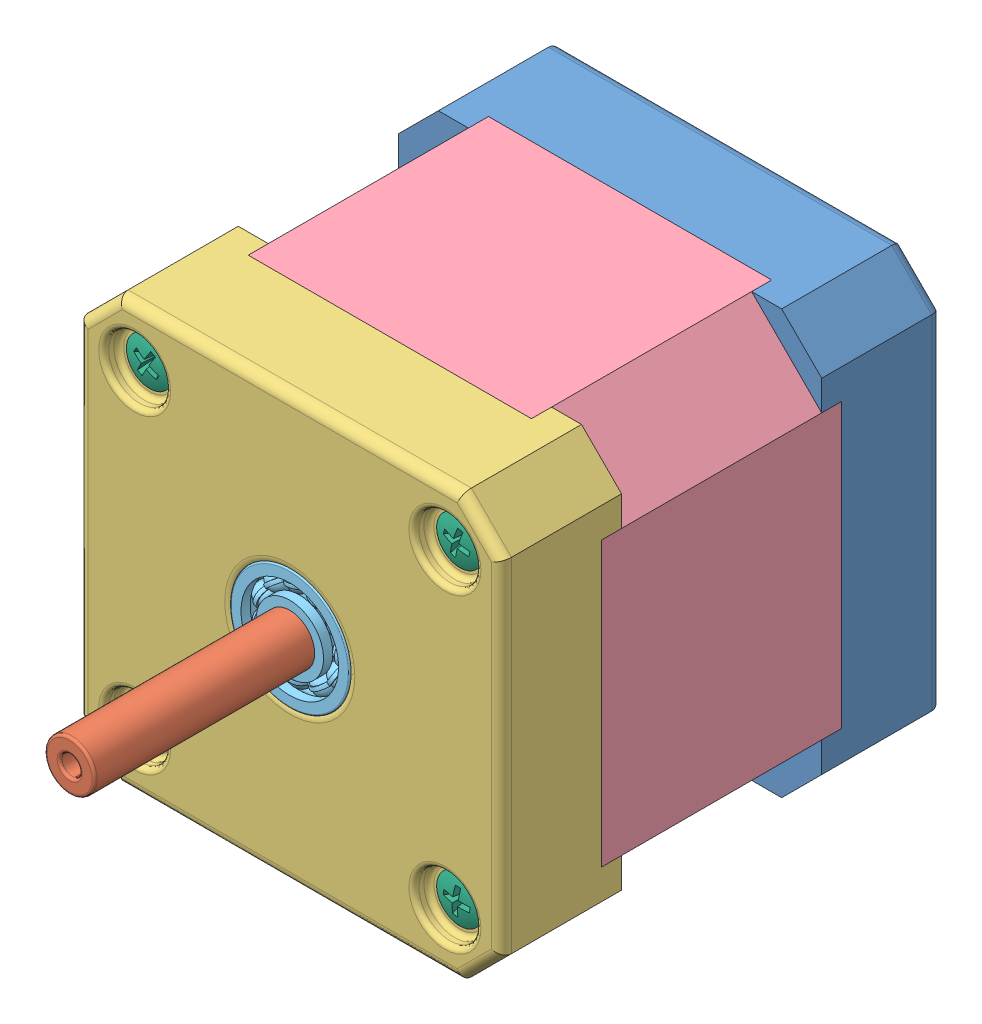
SolidWorks assembly stepper, configuration Default. Lengths in mm.
Overall size (84.6 84.6 136).
10 component instances, 6 part files, 20 mates.
Components (placement in the parent):
- backPlate-1: backPlate [Default] at (30.6882 45.002 54.8281) size (84.6 84.6 28)
- arbre axiale-1: arbre axiale [Default] at (30.6882 45.002 50.8281) x (-0.859783 -0.510659 0) z (0 0 1) size (10 10 136)
- base-1: base [Default] at (72.9882 2.702 142.8281) x (-1 0 0) z (0 0 -1) size (84.6 84.6 24)
- body-1: body [Default] at (30.6882 45.002 74.8281) size (84.6 84.6 48)
- instrument ball bearing_68_am-4: instrument ball bearing_68_am [AFBMA 12.1.4.1 - 0090-24 - Full,DE,AC,Full_68] at (30.6882 45.002 139.3281) x (0 0 1) z (-0.918452 0.395532 0) size (7 24 24)
- instrument ball bearing_68_am-5: instrument ball bearing_68_am [AFBMA 12.1.4.1 - 0090-24 - Full,DE,AC,Full_68] at (30.6882 45.002 61.3281) x (0 0 1) z (-0.976788 0.214208 0) size (7 24 24)
- oval head_am-1: oval head_am [B18.6.7M - M5 x 0.8 x 13 Type I Cross Recessed OHMS --13S] at (61.6882 76.002 140.7742) x (0 0 -1) z (0.276926 0.960891 0) size (14.17 9.3 9.3)
- oval head_am-2: oval head_am [B18.6.7M - M5 x 0.8 x 13 Type I Cross Recessed OHMS --13S] at (61.6882 14.002 140.7742) x (0 0 -1) z (0.994132 -0.108176 0) size (14.17 9.3 9.3)
- oval head_am-3: oval head_am [B18.6.7M - M5 x 0.8 x 13 Type I Cross Recessed OHMS --13S] at (-0.3118 76.002 140.7742) x (0 0 -1) z (0.86317 -0.504913 0) size (14.17 9.3 9.3)
- oval head_am-4: oval head_am [B18.6.7M - M5 x 0.8 x 13 Type I Cross Recessed OHMS --13S] at (-0.3118 14.002 140.7742) x (0 0 -1) z (1 0 0) size (14.17 9.3 9.3)
Mates (geometry in assembly coordinates):
- Concentric1: concentric: cylinder of assembly; cylinder of assembly; cylinder of backPlate-1 through (30.6882 45.002 78.8281) axis (0 0 -1) radius 5; cylinder of arbre axiale-1 through (30.6882 45.002 186.8281) axis (0 0 -1) radius 5
- Coincident1: coincident: plane of assembly; plane of assembly; plane of backPlate-1 through (58.9882 87.302 74.8281) normal (-0.707107 -0.707107 0); plane of body-1 through (58.9882 87.302 122.8281) normal (0.707107 0.707107 0)
- Coincident2: coincident: plane of assembly; plane of assembly; plane of backPlate-1 through (-11.6118 73.302 74.8281) normal (0.707107 -0.707107 0); plane of body-1 through (-11.6118 73.302 122.8281) normal (-0.707107 0.707107 0)
- Coincident3: coincident: plane of assembly; plane of assembly; plane of backPlate-1 through (30.6882 45.002 50.8281) normal (0 0 -1); plane of arbre axiale-1 through (30.6882 45.002 50.8281) normal (0 0 -1)
- Concentric2: concentric: cylinder of assembly; cylinder of assembly; cylinder of arbre axiale-1 through (30.6882 45.002 186.8281) axis (0 0 -1) radius 5; cylinder of base-1 through (30.6882 45.002 118.8281) axis (0 0 1) radius 5
- Coincident4: coincident: plane of assembly; plane of assembly; plane of base-1 through (72.9882 73.302 122.8281) normal (-0.707107 -0.707107 0); plane of body-1 through (58.9882 87.302 122.8281) normal (0.707107 0.707107 0)
- Coincident5: coincident: plane of assembly; plane of assembly; plane of backPlate-1 through (30.6882 45.002 74.8281) normal (0 0 1); plane of body-1 through (30.6882 45.002 74.8281) normal (0 0 -1)
- Coincident6: coincident: plane of assembly; plane of assembly; plane of base-1 through (72.9882 2.702 122.8281) normal (0 0 -1); plane of body-1 through (30.6882 45.002 122.8281) normal (0 0 1)
- Concentric5: concentric: cylinder of assembly; cylinder of assembly; cylinder of arbre axiale-1 through (30.6882 45.002 186.8281) axis (0 0 -1) radius 5; cylinder of instrument ball bearing_68_am-4 through (30.6882 45.002 118.6906) axis (0 0 1) radius 4.5
- Coincident7: coincident: plane of assembly; plane of assembly; plane of base-1 through (72.9882 2.702 142.8281) normal (0 0 1); plane of instrument ball bearing_68_am-4 through (35.316 55.7479 142.8281) normal (0 0 1)
- Concentric6: concentric: cylinder of assembly; cylinder of assembly; cylinder of arbre axiale-1 through (30.6882 45.002 186.8281) axis (0 0 -1) radius 5; cylinder of instrument ball bearing_68_am-5 through (30.6882 45.002 40.6906) axis (0 0 1) radius 4.5
- Coincident8: coincident: plane of assembly; plane of assembly; plane of backPlate-1 through (30.6882 45.002 64.8281) normal (0 0 -1); plane of instrument ball bearing_68_am-5 through (33.1945 56.4305 64.8281) normal (0 0 1)
- Concentric7: concentric: cylinder of assembly; circle of assembly; cylinder of base-1 through (61.6882 76.002 142.8281) axis (0 0 -1) radius 3; circle of oval head_am-1
- Coincident9: coincident: plane of assembly; circle of assembly; plane of base-1 through (61.6882 76.002 139.8281) normal (0 0 1); circle of oval head_am-1
- Concentric9: concentric: cylinder of assembly; cylinder of assembly; cylinder of base-1 through (61.6882 14.002 142.8281) axis (0 0 -1) radius 3; cylinder of oval head_am-2 through (61.6882 14.002 156.6492) axis (0 0 1) radius 4.65
- Coincident10: coincident: plane of assembly; circle of assembly; plane of base-1 through (61.6882 14.002 139.8281) normal (0 0 1); circle of oval head_am-2
- Concentric10: concentric: cylinder of assembly; circle of assembly; cylinder of base-1 through (-0.3118 76.002 142.8281) axis (0 0 -1) radius 3; circle of oval head_am-3
- Concentric11: concentric: cylinder of assembly; circle of assembly; cylinder of base-1 through (-0.3118 14.002 142.8281) axis (0 0 -1) radius 3; circle of oval head_am-4
- Coincident11: coincident: plane of assembly; circle of assembly; plane of base-1 through (-0.3118 76.002 139.8281) normal (0 0 1); circle of oval head_am-3
- Coincident12: coincident: plane of assembly; circle of assembly; plane of base-1 through (-0.3118 14.002 139.8281) normal (0 0 1); circle of oval head_am-4
